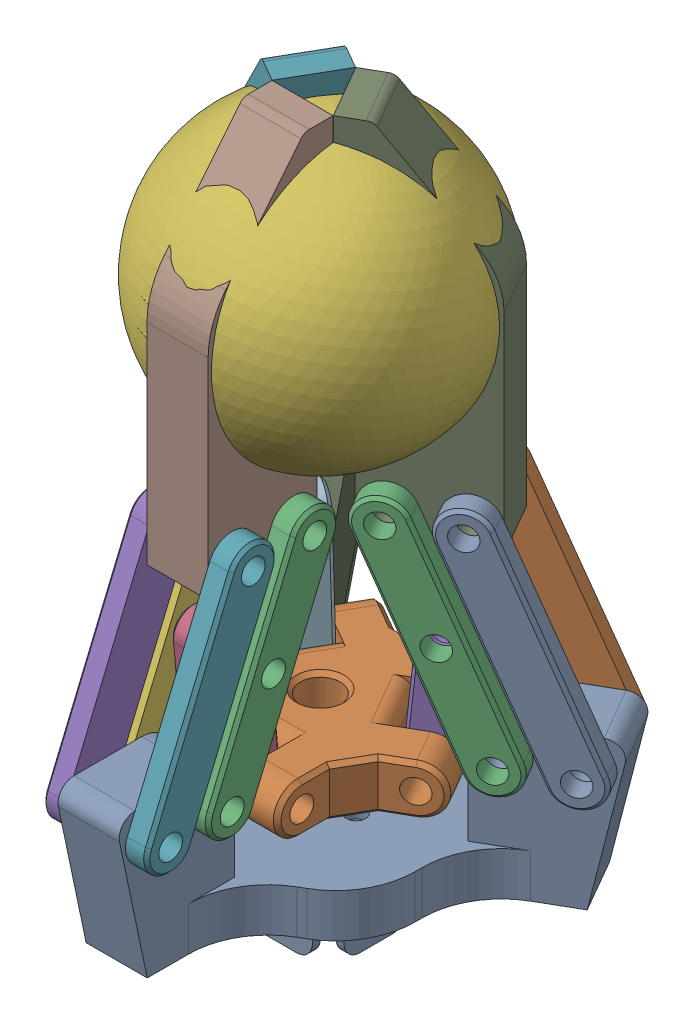
SolidWorks assembly gripper_assemblato_parallelo, configuration Default. Lengths in mm.
Overall size (57.36 89.91 49.68).
21 component instances, 7 part files, 73 mates.
Components (placement in the parent):
- Base_part-1: Base_part [Default] at (-9.4999 -6.0139 17.9318) size (54.42 26.5 47.13)
- Elevetor_part-1: Elevetor_part [Default] at (-9.4999 7.6961 17.9318) size (33.09 6.2 28.84)
- Connecting_rod_3_part-1: Connecting_rod_3_part [Default] at (-4.2999 21.9399 30.3809) x (0 -0.922504 0.385988) z (0 0.385988 0.922504) size (33 2.7 6)
- Connecting_rod_1_part-2: Connecting_rod_1_part [Default] at (-9.4999 15.9997 29.8527) x (0 -0.99607 -0.088569) z (0 0.088569 -0.99607) size (19.5 7.7 5.2)
- Connecting_rod_2_part-1: Connecting_rod_2_part [Default] at (-14.6999 21.9399 38.1309) x (0 0.922504 -0.385988) z (0 0.385988 0.922504) size (33 2.7 6)
- Connecting_rod_3_part-2: Connecting_rod_3_part [Default] at (-14.6999 21.9399 30.3809) x (0 0.922504 -0.385988) z (0 0.385988 0.922504) size (33 2.7 6)
- Connecting_rod_2_part-2: Connecting_rod_2_part [Default] at (-4.2999 21.9399 38.1309) x (0 -0.922504 0.385988) z (0 0.385988 0.922504) size (33 2.7 6)
- Connecting_rod_3_part-3: Connecting_rod_3_part [Default] at (-22.8812 21.9399 16.2105) x (0.334275 0.922504 0.192994) z (0.798912 -0.385988 0.461252) size (33 2.7 6)
- Connecting_rod_3_part-4: Connecting_rod_3_part [Default] at (-17.6812 21.9399 7.2038) x (-0.334275 -0.922504 -0.192994) z (0.798912 -0.385988 0.461252) size (33 2.7 6)
- Connecting_rod_2_part-3: Connecting_rod_2_part [Default] at (-29.5929 21.9399 12.3355) x (0.334275 0.922504 0.192994) z (0.798912 -0.385988 0.461252) size (33 2.7 6)
- Connecting_rod_2_part-4: Connecting_rod_2_part [Default] at (-24.3929 21.9399 3.3288) x (-0.334275 -0.922504 -0.192994) z (0.798912 -0.385988 0.461252) size (33 2.7 6)
- Connecting_rod_1_part-3: Connecting_rod_1_part [Default] at (-19.8238 15.9997 11.9713) x (0.076703 -0.99607 0.044284) z (0.862622 0.088569 0.498035) size (19.5 7.7 5.2)
- Connecting_rod_2_part-5: Connecting_rod_2_part [Default] at (10.5931 21.9399 12.3355) x (0.334275 -0.922504 -0.192994) z (-0.798912 -0.385988 0.461252) size (33 2.7 6)
- Connecting_rod_2_part-6: Connecting_rod_2_part [Default] at (5.3931 21.9399 3.3288) x (-0.334275 0.922504 0.192994) z (-0.798912 -0.385988 0.461252) size (33 2.7 6)
- Connecting_rod_3_part-5: Connecting_rod_3_part [Default] at (3.8814 21.9399 16.2105) x (0.334275 -0.922504 -0.192994) z (-0.798912 -0.385988 0.461252) size (33 2.7 6)
- Connecting_rod_3_part-6: Connecting_rod_3_part [Default] at (-1.3186 21.9399 7.2038) x (-0.334275 0.922504 0.192994) z (-0.798912 -0.385988 0.461252) size (33 2.7 6)
- Connecting_rod_1_part-4: Connecting_rod_1_part [Default] at (0.642 13.6363 12.0763) x (0.076703 0.99607 -0.044284) z (-0.862622 0.088569 0.498035) size (19.5 7.7 5.2)
- ball-2: ball [Default] at (-9.4999 56.0442 17.9318) x (0.987141 -0.049572 0.151971) z (-0.141927 0.165625 0.975923) size (36 36 36) (hidden)
- Gripper1_part-1: Gripper1_part [Default] at (-13.1704 46.3937 15.8126) x (0.866025 0 0.5) z (0 -1 0) size (15.75 7.7 45)
- Gripper1_part-2: Gripper1_part [Default] at (-9.4999 46.3937 22.1701) x (0 0 -1) z (0 -1 0) size (15.75 7.7 45)
- Gripper1_part-3: Gripper1_part [Default] at (-5.8294 46.3937 15.8126) x (-0.866025 0 0.5) z (0 -1 0) size (15.75 7.7 45)
Mates (geometry in assembly coordinates):
- Coincidente18: coincident: plane of Base_part-1 through (-5.6499 -0.5139 47.5918) normal (1 0 0); plane of Connecting_rod_2_part-2 through (-5.6499 31.5136 58.9555) normal (-1 0 0)
- Concentrico16: concentric: cylinder of Base_part-1 through (-5.6499 9.4861 43.3418) axis (-1 0 0) radius 1.5; cylinder of Connecting_rod_2_part-2 through (-2.9499 9.4861 43.3418) axis (-1 0 0) radius 1.5
- Coincidente8: coincident: plane of Base_part-1 through (-5.6499 -0.5139 47.5918) normal (1 0 0); plane of Connecting_rod_3_part-1 through (-5.6499 31.5136 51.2055) normal (-1 0 0)
- Concentrico8: concentric: cylinder of Connecting_rod_3_part-1 through (-2.9499 20.4999 43.3986) axis (-1 0 0) radius 1.5; cylinder of Connecting_rod_1_part-2 through (-13.3499 20.4999 43.3986) axis (1 0 0) radius 1.5
- Coincidente9: coincident: plane of Connecting_rod_3_part-1 through (-5.6499 31.5136 51.2055) normal (-1 0 0); plane of Connecting_rod_1_part-2 through (-5.6499 20.4999 43.3986) normal (1 0 0)
- Concentrico7: concentric: cylinder of Base_part-1 through (-5.6499 9.4861 35.5918) axis (-1 0 0) radius 1.5; cylinder of Connecting_rod_3_part-1 through (-2.9499 9.4861 35.5918) axis (-1 0 0) radius 1.5
- Concentrico1: concentric: cylinder of Base_part-1 through (-5.6499 9.4861 35.5918) axis (-1 0 0) radius 1.5; cylinder of Connecting_rod_3_part-2 through (-16.0499 9.4861 35.5918) axis (1 0 0) radius 1.5
- Coincidente1: coincident: plane of Base_part-1 through (-13.3499 -0.5139 32.5918) normal (-1 0 0); plane of Connecting_rod_3_part-2 through (-13.3499 9.4861 35.5918) normal (1 0 0)
- Concentrico3: concentric: cylinder of Base_part-1 through (-5.6499 9.4861 43.3418) axis (-1 0 0) radius 1.5; cylinder of Connecting_rod_2_part-1 through (-16.0499 9.4861 43.3418) axis (1 0 0) radius 1.5
- Coincidente3: coincident: plane of Base_part-1 through (-13.3499 -0.5139 32.5918) normal (-1 0 0); plane of Connecting_rod_2_part-1 through (-13.3499 9.4861 43.3418) normal (1 0 0)
- Concentrico5: concentric: cylinder of Connecting_rod_1_part-2 through (-13.3499 20.4999 43.3986) axis (1 0 0) radius 1.5; cylinder of Connecting_rod_3_part-2 through (-16.0499 20.4999 43.3986) axis (1 0 0) radius 1.5
- Coincidente5: coincident: plane of Connecting_rod_1_part-2 through (-13.3499 20.4999 43.3986) normal (-1 0 0); plane of Connecting_rod_3_part-2 through (-13.3499 9.4861 35.5918) normal (1 0 0)
- Concentrico10: concentric: cylinder of Base_part-1 through (-26.7189 9.4861 12.4359) axis (0.5 0 -0.866025) radius 1.5; cylinder of Connecting_rod_3_part-4 through (-21.5189 9.4861 3.4293) axis (-0.5 0 0.866025) radius 1.5
- Coincidente12: coincident: plane of Base_part-1 through (-20.2708 -0.5139 7.2676) normal (0.5 0 -0.866025); plane of Connecting_rod_3_part-4 through (-36.3908 31.5136 -2.0393) normal (-0.5 0 0.866025)
- Concentrico11: concentric: cylinder of Base_part-1 through (-26.7189 9.4861 12.4359) axis (0.5 0 -0.866025) radius 1.5; cylinder of Connecting_rod_3_part-3 through (-28.0689 9.4861 14.7742) axis (0.5 0 -0.866025) radius 1.5
- Coincidente13: coincident: plane of Base_part-1 through (-37.1112 -0.5139 6.4359) normal (-0.5 0 0.866025); plane of Connecting_rod_3_part-3 through (-26.7189 9.4861 12.4359) normal (0.5 0 -0.866025)
- Concentrico12: concentric: cylinder of Base_part-1 through (-33.4306 9.4861 8.5609) axis (0.5 0 -0.866025) radius 1.5; cylinder of Connecting_rod_2_part-3 through (-34.7806 9.4861 10.8992) axis (0.5 0 -0.866025) radius 1.5
- Coincidente14: coincident: plane of Base_part-1 through (-37.1112 -0.5139 6.4359) normal (-0.5 0 0.866025); plane of Connecting_rod_2_part-3 through (-33.4306 9.4861 8.5609) normal (0.5 0 -0.866025)
- Concentrico13: concentric: cylinder of Base_part-1 through (-33.4306 9.4861 8.5609) axis (0.5 0 -0.866025) radius 1.5; cylinder of Connecting_rod_2_part-4 through (-28.2306 9.4861 -0.4457) axis (-0.5 0 0.866025) radius 1.5
- Coincidente15: coincident: plane of Base_part-1 through (-20.2708 -0.5139 7.2676) normal (0.5 0 -0.866025); plane of Connecting_rod_2_part-4 through (-43.1025 31.5136 -5.9143) normal (-0.5 0 0.866025)
- Concentrico14: concentric: cylinder of Connecting_rod_3_part-4 through (-28.2799 20.4999 -0.4742) axis (-0.5 0 0.866025) radius 1.5; cylinder of Connecting_rod_1_part-3 through (-29.6299 20.4999 1.8641) axis (-0.5 0 0.866025) radius 1.5
- Coincidente17: coincident: plane of Connecting_rod_3_part-3 through (-26.7189 9.4861 12.4359) normal (0.5 0 -0.866025); plane of Connecting_rod_1_part-3 through (-33.4799 20.4999 8.5325) normal (-0.5 0 0.866025)
- Coincidente16: coincident: plane of Connecting_rod_3_part-4 through (-36.3908 31.5136 -2.0393) normal (-0.5 0 0.866025); plane of Connecting_rod_1_part-3 through (-29.6299 20.4999 1.8641) normal (0.5 0 -0.866025)
- Concentrico15: concentric: cylinder of Connecting_rod_3_part-3 through (-34.8299 20.4999 10.8708) axis (0.5 0 -0.866025) radius 1.5; cylinder of Connecting_rod_1_part-3 through (-29.6299 20.4999 1.8641) axis (-0.5 0 0.866025) radius 1.5
- Concentrico17: concentric: cylinder of Base_part-1 through (10.5808 9.4861 1.8926) axis (0.5 0 0.866025) radius 1.5; cylinder of Connecting_rod_2_part-5 through (15.7808 9.4861 10.8992) axis (-0.5 0 -0.866025) radius 1.5
- Concentrico19: concentric: cylinder of Base_part-1 through (10.5808 9.4861 1.8926) axis (0.5 0 0.866025) radius 1.5; cylinder of Connecting_rod_2_part-6 through (9.2308 9.4861 -0.4457) axis (0.5 0 0.866025) radius 1.5
- Coincidente19: coincident: plane of Base_part-1 through (14.2614 -0.5139 -0.2324) normal (-0.5 0 -0.866025); plane of Connecting_rod_2_part-6 through (10.5808 9.4861 1.8926) normal (0.5 0 0.866025)
- Coincidente20: coincident: plane of Base_part-1 through (5.121 -0.5139 13.9359) normal (0.5 0 0.866025); plane of Connecting_rod_2_part-5 through (27.9527 31.5136 0.7541) normal (-0.5 0 -0.866025)
- Concentrico20: concentric: cylinder of Base_part-1 through (3.8691 9.4861 5.7676) axis (0.5 0 0.866025) radius 1.5; cylinder of Connecting_rod_3_part-5 through (9.0691 9.4861 14.7742) axis (-0.5 0 -0.866025) radius 1.5
- Coincidente24: coincident: plane of Connecting_rod_3_part-5 through (21.241 31.5136 4.6291) normal (-0.5 0 -0.866025); plane of Connecting_rod_1_part-4 through (2.1095 19.8289 15.6746) normal (0.5 0 0.866025)
- Coincidente23: coincident: plane of Connecting_rod_3_part-6 through (3.8691 9.4861 5.7676) normal (0.5 0 0.866025); plane of Connecting_rod_1_part-4 through (-1.7405 19.8289 9.0062) normal (-0.5 0 -0.866025)
- Concentrico24: concentric: cylinder of Connecting_rod_3_part-6 through (9.2801 20.4999 -0.4742) axis (0.5 0 0.866025) radius 1.5; cylinder of Connecting_rod_1_part-4 through (10.6301 20.4999 1.8641) axis (0.5 0 0.866025) radius 1.5
- Concentrico23: concentric: cylinder of Connecting_rod_3_part-5 through (15.8301 20.4999 10.8708) axis (-0.5 0 -0.866025) radius 1.5; cylinder of Connecting_rod_1_part-4 through (10.6301 20.4999 1.8641) axis (0.5 0 0.866025) radius 1.5
- Coincidente22: coincident: plane of Base_part-1 through (14.2614 -0.5139 -0.2324) normal (-0.5 0 -0.866025); plane of Connecting_rod_3_part-6 through (3.8691 9.4861 5.7676) normal (0.5 0 0.866025)
- Coincidente21: coincident: plane of Base_part-1 through (5.121 -0.5139 13.9359) normal (0.5 0 0.866025); plane of Connecting_rod_3_part-5 through (21.241 31.5136 4.6291) normal (-0.5 0 -0.866025)
- Concentrico22: concentric: cylinder of Base_part-1 through (3.8691 9.4861 5.7676) axis (0.5 0 0.866025) radius 1.5; cylinder of Connecting_rod_3_part-6 through (2.5191 9.4861 3.4293) axis (0.5 0 0.866025) radius 1.5
- Concentrico25: concentric: cylinder of Elevetor_part-1 through (-10.5874 19.8289 -6.3171) axis (0.5 0 0.866025) radius 1.5; cylinder of Connecting_rod_1_part-4 through (-1.7405 19.8289 9.0062) axis (0.5 0 0.866025) radius 1.5
- Coincidente25: coincident: plane of Elevetor_part-1 through (1.269 22.9289 7.2687) normal (0.5 0 0.866025); plane of Connecting_rod_1_part-4 through (-1.7405 19.8289 9.0062) normal (-0.5 0 -0.866025)
- Coincidente26: coincident: plane of Elevetor_part-1 through (5.119 22.9289 13.9371) normal (-0.5 0 -0.866025); plane of Connecting_rod_1_part-4 through (2.1095 19.8289 15.6746) normal (0.5 0 0.866025)
- Concentrico26: concentric: cylinder of Elevetor_part-1 through (-10.5874 19.8289 -6.3171) axis (0.5 0 0.866025) radius 1.5; cylinder of Connecting_rod_1_part-4 through (-1.7405 19.8289 9.0062) axis (0.5 0 0.866025) radius 1.5
- Concentrico27: concentric: cylinder of Elevetor_part-1 through (-29.6486 19.8289 30.4651) axis (0.5 0 -0.866025) radius 1.5; cylinder of Connecting_rod_1_part-3 through (-17.2593 19.8289 9.0062) axis (-0.5 0 0.866025) radius 1.5
- Coincidente30: coincident: plane of Elevetor_part-1 through (-13.3499 22.9289 32.5894) normal (1 0 0); plane of Connecting_rod_1_part-2 through (-13.3499 20.4999 43.3986) normal (-1 0 0)
- Coincidente29: coincident: plane of Elevetor_part-1 through (-5.6499 22.9289 32.5894) normal (-1 0 0); plane of Connecting_rod_1_part-2 through (-5.6499 20.4999 43.3986) normal (1 0 0)
- Concentrico30: concentric: cylinder of Elevetor_part-1 through (7.619 19.8289 29.1144) axis (-1 0 0) radius 1.5; cylinder of Connecting_rod_1_part-2 through (-13.3499 19.8289 29.1144) axis (1 0 0) radius 1.5
- Concentrico29: concentric: cylinder of Elevetor_part-1 through (7.619 19.8289 29.1144) axis (-1 0 0) radius 1.5; cylinder of Connecting_rod_1_part-2 through (-13.3499 19.8289 29.1144) axis (1 0 0) radius 1.5
- Coincidente28: coincident: plane of Elevetor_part-1 through (-20.2688 22.9289 7.2687) normal (-0.5 0 0.866025); plane of Connecting_rod_1_part-3 through (-29.6299 20.4999 1.8641) normal (0.5 0 -0.866025)
- Coincidente27: coincident: plane of Elevetor_part-1 through (-24.1188 22.9289 13.9371) normal (0.5 0 -0.866025); plane of Connecting_rod_1_part-3 through (-33.4799 20.4999 8.5325) normal (-0.5 0 0.866025)
- Concentrico28: concentric: cylinder of Elevetor_part-1 through (-29.6486 19.8289 30.4651) axis (0.5 0 -0.866025) radius 1.5; cylinder of Connecting_rod_1_part-3 through (-17.2593 19.8289 9.0062) axis (-0.5 0 0.866025) radius 1.5
- DistanzaLimite2: limit distance = 17.2428 mm: plane of Elevetor_part-1 through (-9.4999 4.5961 17.9318) normal (0 -1 0); plane of Base_part-1 through (-9.4999 -0.5139 17.9318) normal (0 1 0)
- Concentrico31: concentric: cylinder of Connecting_rod_3_part-3 through (-41.5908 31.5136 6.9673) axis (0.5 0 -0.866025) radius 1.5; cylinder of Gripper1_part-1 through (-40.2408 31.5136 4.6291) axis (0.5 0 -0.866025) radius 1.5
- Concentrico32: concentric: cylinder of Connecting_rod_3_part-4 through (-35.0408 31.5136 -4.3776) axis (-0.5 0 0.866025) radius 1.5; cylinder of Gripper1_part-1 through (-40.2408 31.5136 4.6291) axis (0.5 0 -0.866025) radius 1.5
- Coincidente31: coincident: plane of Connecting_rod_3_part-3 through (-26.7189 9.4861 12.4359) normal (0.5 0 -0.866025); plane of Gripper1_part-1 through (-37.6427 43.5136 6.1291) normal (-0.5 0 0.866025)
- Coincidente32: coincident: plane of Connecting_rod_3_part-4 through (-36.3908 31.5136 -2.0393) normal (-0.5 0 0.866025); plane of Gripper1_part-1 through (-33.7927 43.5136 -0.5393) normal (0.5 0 -0.866025)
- Concentrico33: concentric: cylinder of Connecting_rod_2_part-3 through (-48.3025 31.5136 3.0923) axis (0.5 0 -0.866025) radius 1.5; cylinder of Gripper1_part-1 through (-46.9525 31.5136 0.7541) axis (0.5 0 -0.866025) radius 1.5
- Concentrico34: concentric: cylinder of Connecting_rod_2_part-4 through (-41.7525 31.5136 -8.2526) axis (-0.5 0 0.866025) radius 1.5; cylinder of Gripper1_part-1 through (-46.9525 31.5136 0.7541) axis (0.5 0 -0.866025) radius 1.5
- Coincidente33: coincident: plane of Connecting_rod_2_part-4 through (-43.1025 31.5136 -5.9143) normal (-0.5 0 0.866025); plane of Gripper1_part-1 through (-33.7927 43.5136 -0.5393) normal (0.5 0 -0.866025)
- Coincidente34: coincident: plane of Connecting_rod_2_part-3 through (-33.4306 9.4861 8.5609) normal (0.5 0 -0.866025); plane of Gripper1_part-1 through (-37.6427 43.5136 6.1291) normal (-0.5 0 0.866025)
- Concentrico35: concentric: cylinder of Connecting_rod_3_part-2 through (-16.0499 31.5136 51.2055) axis (1 0 0) radius 1.5; cylinder of Gripper1_part-2 through (-5.6499 31.5136 51.2055) axis (-1 0 0) radius 1.5
- Concentrico36: concentric: cylinder of Connecting_rod_2_part-1 through (-16.0499 31.5136 58.9555) axis (1 0 0) radius 1.5; cylinder of Gripper1_part-2 through (-5.6499 31.5136 58.9555) axis (-1 0 0) radius 1.5
- Concentrico37: concentric: cylinder of Connecting_rod_3_part-1 through (-2.9499 31.5136 51.2055) axis (-1 0 0) radius 1.5; cylinder of Gripper1_part-2 through (-5.6499 31.5136 51.2055) axis (-1 0 0) radius 1.5
- Concentrico38: concentric: cylinder of Connecting_rod_2_part-2 through (-2.9499 31.5136 58.9555) axis (-1 0 0) radius 1.5; cylinder of Gripper1_part-2 through (-5.6499 31.5136 58.9555) axis (-1 0 0) radius 1.5
- Coincidente35: coincident: plane of Connecting_rod_3_part-2 through (-13.3499 9.4861 35.5918) normal (1 0 0); plane of Gripper1_part-2 through (-13.3499 43.5136 48.2055) normal (-1 0 0)
- Coincidente36: coincident: plane of Connecting_rod_2_part-1 through (-13.3499 9.4861 43.3418) normal (1 0 0); plane of Gripper1_part-2 through (-13.3499 43.5136 48.2055) normal (-1 0 0)
- Coincidente37: coincident: plane of Connecting_rod_2_part-2 through (-5.6499 31.5136 58.9555) normal (-1 0 0); plane of Gripper1_part-2 through (-5.6499 43.5136 48.2055) normal (1 0 0)
- Coincidente38: coincident: plane of Connecting_rod_3_part-1 through (-5.6499 31.5136 51.2055) normal (-1 0 0); plane of Gripper1_part-2 through (-5.6499 43.5136 48.2055) normal (1 0 0)
- Concentrico39: concentric: cylinder of Connecting_rod_3_part-5 through (22.591 31.5136 6.9673) axis (-0.5 0 -0.866025) radius 1.5; cylinder of Gripper1_part-3 through (17.391 31.5136 -2.0393) axis (0.5 0 0.866025) radius 1.5
- Concentrico40: concentric: cylinder of Connecting_rod_3_part-6 through (16.041 31.5136 -4.3776) axis (0.5 0 0.866025) radius 1.5; cylinder of Gripper1_part-3 through (17.391 31.5136 -2.0393) axis (0.5 0 0.866025) radius 1.5
- Concentrico41: concentric: cylinder of Connecting_rod_2_part-6 through (22.7527 31.5136 -8.2526) axis (0.5 0 0.866025) radius 1.5; cylinder of Gripper1_part-3 through (24.1027 31.5136 -5.9143) axis (0.5 0 0.866025) radius 1.5
- Concentrico42: concentric: cylinder of Connecting_rod_2_part-5 through (29.3027 31.5136 3.0923) axis (-0.5 0 -0.866025) radius 1.5; cylinder of Gripper1_part-3 through (24.1027 31.5136 -5.9143) axis (0.5 0 0.866025) radius 1.5
- Coincidente39: coincident: plane of Connecting_rod_3_part-5 through (21.241 31.5136 4.6291) normal (-0.5 0 -0.866025); plane of Gripper1_part-3 through (18.6429 43.5136 6.1291) normal (0.5 0 0.866025)
- Coincidente40: coincident: plane of Connecting_rod_2_part-5 through (27.9527 31.5136 0.7541) normal (-0.5 0 -0.866025); plane of Gripper1_part-3 through (18.6429 43.5136 6.1291) normal (0.5 0 0.866025)
- Coincidente41: coincident: plane of Connecting_rod_2_part-6 through (10.5808 9.4861 1.8926) normal (0.5 0 0.866025); plane of Gripper1_part-3 through (14.7929 43.5136 -0.5393) normal (-0.5 0 -0.866025)
- Coincidente42: coincident: plane of Connecting_rod_3_part-6 through (3.8691 9.4861 5.7676) normal (0.5 0 0.866025); plane of Gripper1_part-3 through (14.7929 43.5136 -0.5393) normal (-0.5 0 -0.866025)
